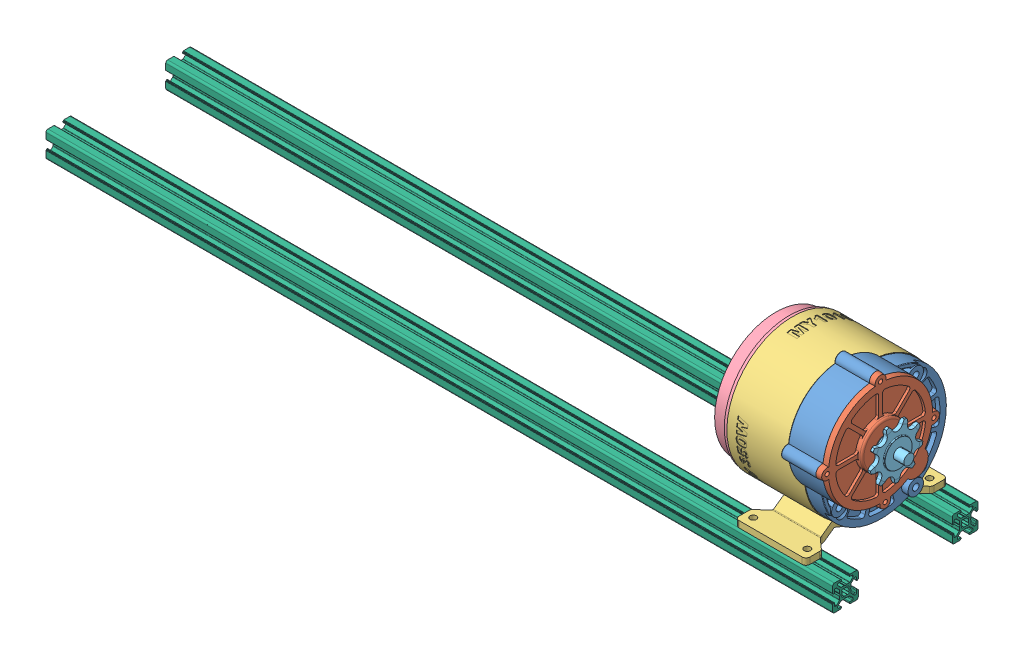
SolidWorks assembly Motor Mounting, configuration Default. Lengths in mm.
7 component instances, 6 part files, 17 mates.
Components (placement in the parent):
- MY1016Z3 DC MOTOR 24V 350W-03-2-1: MY1016Z3 DC MOTOR 24V 350W-03-2 [Default] at (416.9594 57 -158.0968) x (0 -0.707107 0.707107) z (1 0 0) size (101 130.5 34)
- MY1016Z3 DC MOTOR 24V 350W-02-1: MY1016Z3 DC MOTOR 24V 350W-02 [Default] at (452.9594 84.5772 -130.5196) x (0 -0.707107 0.707107) z (1 0 0) size (82 90 7)
- MY1016Z3 DC MOTOR 24V 350W-04-2-1: MY1016Z3 DC MOTOR 24V 350W-04-2 [Default] at (386.9594 57 -158.0968) x (0 -0.707107 0.707107) z (1 0 0) size (130.2 130.2 65.5)
- MY1016Z3 DC MOTOR 24V 350W-05-1: MY1016Z3 DC MOTOR 24V 350W-05 [Default] at (356.9594 57 -158.0968) x (0 0.707107 -0.707107) z (1 0 0) size (101 101 22)
- MY1016Z3 DC MOTOR 24V 350W-01-1: MY1016Z3 DC MOTOR 24V 350W-01 [Default] at (464.4594 84.5772 -130.5196) x (0 0 -1) z (1 0 0) size (40.71 40.13 26)
- Motor holding Exrusion-1: Motor holding Exrusion [Default<As Machined>] at (444.5495 -9.9985 -111.5957) x (-1 0 0) z (0 0 1) size (611 20 20)
- Motor holding Exrusion-2: Motor holding Exrusion [Default<As Machined>] at (-166.4505 -10.0002 -204.5979) size (611 20 20)
Mates (geometry in assembly coordinates):
- Coincident1: coincident: plane of ? through (351.651 84.5772 -109.7696) normal (1 0 0); plane of ? through (351.651 70.7886 -144.3082) normal (-1 0 0)
- Concentric1: concentric: cylinder of ? through (351.651 84.5772 -89.0196) axis (1 0 0) radius 1.65; cylinder of ? through (351.651 84.5772 -89.0196) axis (-1 0 0) radius 1.65
- Concentric2: concentric: cylinder of ? through (351.651 126.0772 -130.5196) axis (1 0 0) radius 1.65; cylinder of ? through (351.651 126.0772 -130.5196) axis (-1 0 0) radius 1.65
- Coincident2: coincident: plane of ? through (319.651 57 -158.0968) normal (-1 0 0); plane of ? through (319.651 57 -158.0968) normal (1 0 0)
- Concentric4: concentric: cylinder of ? through (333.651 35.25 -120.4247) axis (1 0 0) radius 2.5; cylinder of ? through (319.651 35.25 -120.4247) axis (1 0 0) radius 2.5
- Concentric5: concentric: cylinder of ? through (333.651 94.6721 -179.8468) axis (1 0 0) radius 2.5; cylinder of ? through (319.651 94.6721 -179.8468) axis (1 0 0) radius 2.5
- Coincident21: coincident: plane of ? through (279.151 0 -191.0968) normal (0 -1 0); plane of assembly through (0 0 0) normal (0 1 0)
- Concentric34: concentric: cylinder of ? through (319.651 87.7591 -188.8559) axis (1 0 0) radius 1.65; cylinder of ? through (259.651 87.7591 -188.8559) axis (1 0 0) radius 1.65
- Concentric35: concentric: cylinder of ? through (319.651 26.2409 -127.3376) axis (1 0 0) radius 1.65; cylinder of ? through (259.651 26.2409 -127.3376) axis (1 0 0) radius 1.65
- Coincident23: coincident: plane of ? through (259.651 57 -158.0968) normal (-1 0 0); plane of ? through (259.651 57 -158.0968) normal (1 0 0)
- Concentric36: concentric: cylinder of ? through (358.651 84.5772 -130.5196) axis (1 0 0) radius 7; cylinder of ? through (351.651 84.5772 -130.5196) axis (1 0 0) radius 5.5
- Coincident24: coincident: plane of ? through (351.651 84.5772 -109.7696) normal (1 0 0); plane of ? through (351.651 84.5772 -130.5196) normal (-1 0 0)
- Coincident25: coincident: plane of ? through (279.151 0 -125.0968) normal (0 -1 0); plane of Motor holding Exrusion-1 through (-166.4505 0 -103.0968) normal (0 1 0)
- Coincident27: coincident: line of ? through (273.151 0 -103.0968) axis (1 0 0); line of Motor holding Exrusion-1 through (-166.4505 0 -103.0968) axis (1 0 0)
- Coincident28: coincident: plane of ? through (279.151 0 -191.0968) normal (0 -1 0); plane of Motor holding Exrusion-2 through (444.5496 0 -213.0968) normal (0 1 0)
- Coincident29: coincident: line of ? through (273.151 0 -213.0968) axis (1 0 0); line of Motor holding Exrusion-2 through (444.5496 0 -213.0968) axis (-1 0 0)
- Coincident30: coincident: line of assembly; line of assembly; line of Motor holding Exrusion-1 through (-166.4505 0 -115.3446) axis (0 0 -1); line of Motor holding Exrusion-2 through (-166.4504 0 -213.0968) axis (0 0 1)
